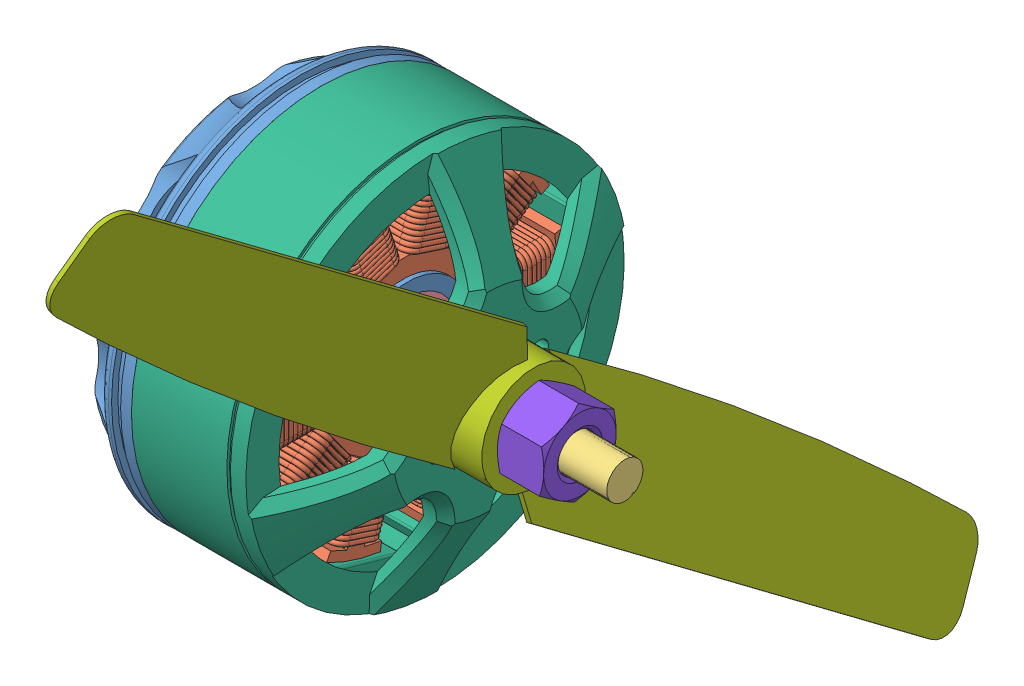
SolidWorks assembly Assembly motor-170555, configuration Default. Lengths in mm.
Overall size (42 88.43 114.12).
9 component instances, 8 part files, 16 mates.
Components (placement in the parent):
- stator-170555-1: stator-170555 [Default] at (-0.6979 16.7893 39.6575) size (17.16 41.8 41.8)
- coil-170555-1: coil-170555 [Default] at (15.8021 16.7893 39.6575) x (0 1 0) z (0 0 1) size (35.65 8.95 36)
- axle-170555-1: axle-170555 [Default] at (-1.6979 16.7893 39.6575) x (0 -0.466036 0.884766) z (0 0.884766 0.466036) size (4 42 4)
- radial ball bearing_68_skf-2: radial ball bearing_68_skf [SKF - 604 - 8,SI,NC,8_68] at (14.3021 16.7893 39.6575) x (-1 0 0) z (0 0.799937 -0.600084) size (4 12 12)
- radial ball bearing_68_skf-3: radial ball bearing_68_skf [SKF - 604 - 8,SI,NC,8_68] at (1.3021 16.7893 39.6575) x (-1 0 0) z (0 0.799937 -0.600084) size (4 12 12)
- circlip-170555-1: circlip-170555 [Default] at (-0.8979 16.7893 39.6575) x (0 -0.557739 -0.830017) z (0 0.830017 -0.557739) size (5 0.2 4.35)
- bell-170555-1: bell-170555 [Default] at (25.2321 16.7893 39.6575) x (1 0 0) z (0 0.938754 0.344587) size (18.53 41.8 41.8)
- propellar-170555-1: propellar-170555 [Default] at (27.7321 16.7893 39.6575) x (0 0.815298 -0.579041) z (0 -0.579041 -0.815298) size (18.26 5 127)
- hex nut style 2_am-1: hex nut style 2_am [B18.2.4.2M - Hex nut, Style 2,  M5 x 0.8 --D-N] at (30.2321 16.7893 39.6575) x (0 0.044381 0.999015) z (-1 0 0) size (8 9.24 5.1)
Mates (geometry in assembly coordinates):
- Concentric3: concentric anti-aligned: cylinder of stator-170555-1 through (-0.6979 16.7893 39.6575) axis (-1 0 0) radius 7; cylinder of coil-170555-1 through (7.8021 16.7893 39.6575) axis (1 0 0) radius 7
- Coincident1: coincident anti-aligned: plane of stator-170555-1 through (7.8021 24.7893 39.6575) normal (1 0 0); plane of coil-170555-1 through (7.8021 16.7893 39.6575) normal (-1 0 0)
- Concentric4: concentric aligned: cylinder of stator-170555-1 through (-0.6979 16.7893 39.6575) axis (-1 0 0) radius 2; cylinder of axle-170555-1 through (40.3021 16.7893 39.6575) axis (-1 0 0) radius 2
- Concentric5: concentric aligned: cylinder of axle-170555-1 through (40.3021 16.7893 39.6575) axis (-1 0 0) radius 2; cylinder of radial ball bearing_68_skf-2 through (34.9396 16.7893 39.6575) axis (-1 0 0) radius 2
- Coincident2: coincident anti-aligned: plane of stator-170555-1 through (12.3021 22.2893 39.6575) normal (1 0 0); plane of radial ball bearing_68_skf-2 through (12.3021 20.2698 44.2971) normal (-1 0 0)
- Concentric8: concentric aligned: cylinder of axle-170555-1 through (40.3021 16.7893 39.6575) axis (-1 0 0) radius 2; cylinder of radial ball bearing_68_skf-3 through (21.9396 16.7893 39.6575) axis (-1 0 0) radius 2
- Coincident3: coincident aligned: plane of stator-170555-1 through (3.3021 18.7893 39.6575) normal (-1 0 0); circle of radial ball bearing_68_skf-3
- Coincident4: coincident aligned: plane of axle-170555-1 through (-0.6979 15.0198 38.7254) normal (-1 0 0); plane of radial ball bearing_68_skf-3 through (-0.6979 18.1095 41.4173) normal (-1 0 0)
- Concentric9: concentric anti-aligned: cylinder of axle-170555-1 through (40.3021 16.7893 39.6575) axis (-1 0 0) radius 2; cylinder of circlip-170555-1 through (-1.0979 16.7893 39.6575) axis (1 0 0) radius 1.5
- Coincident5: coincident anti-aligned: circle of axle-170555-1; plane of circlip-170555-1 through (-0.8979 14.4202 39.2736) normal (1 0 0)
- Concentric10: concentric aligned: cylinder of axle-170555-1 through (40.3021 16.7893 39.6575) axis (-1 0 0) radius 2; cylinder of bell-170555-1 through (19.3301 16.7893 39.6575) axis (-1 0 0) radius 2
- Coincident6: coincident anti-aligned: plane of stator-170555-1 through (6.7021 37.6893 39.6575) normal (1 0 0); plane of bell-170555-1 through (6.7021 23.9912 20.0375) normal (-1 0 0)
- Concentric11: concentric aligned: cylinder of axle-170555-1 through (40.3021 16.7893 39.6575) axis (-1 0 0) radius 2; cylinder of propellar-170555-1 through (30.2321 16.7893 39.6575) axis (-1 0 0) radius 2
- Coincident7: coincident anti-aligned: plane of bell-170555-1 through (25.2321 17.4785 37.78) normal (1 0 0); plane of propellar-170555-1 through (25.2321 16.7893 39.6575) normal (-1 0 0)
- Concentric12: concentric aligned: cylinder of axle-170555-1 through (40.3021 16.7893 39.6575) axis (-1 0 0) radius 2; cylinder of hex nut style 2_am-1 through (55.2697 16.7893 39.6575) axis (-1 0 0) radius 2.5
- Coincident8: coincident anti-aligned: plane of propellar-170555-1 through (30.2321 16.7893 39.6575) normal (1 0 0); plane of hex nut style 2_am-1 through (30.2321 21.4036 39.4525) normal (-1 0 0)
